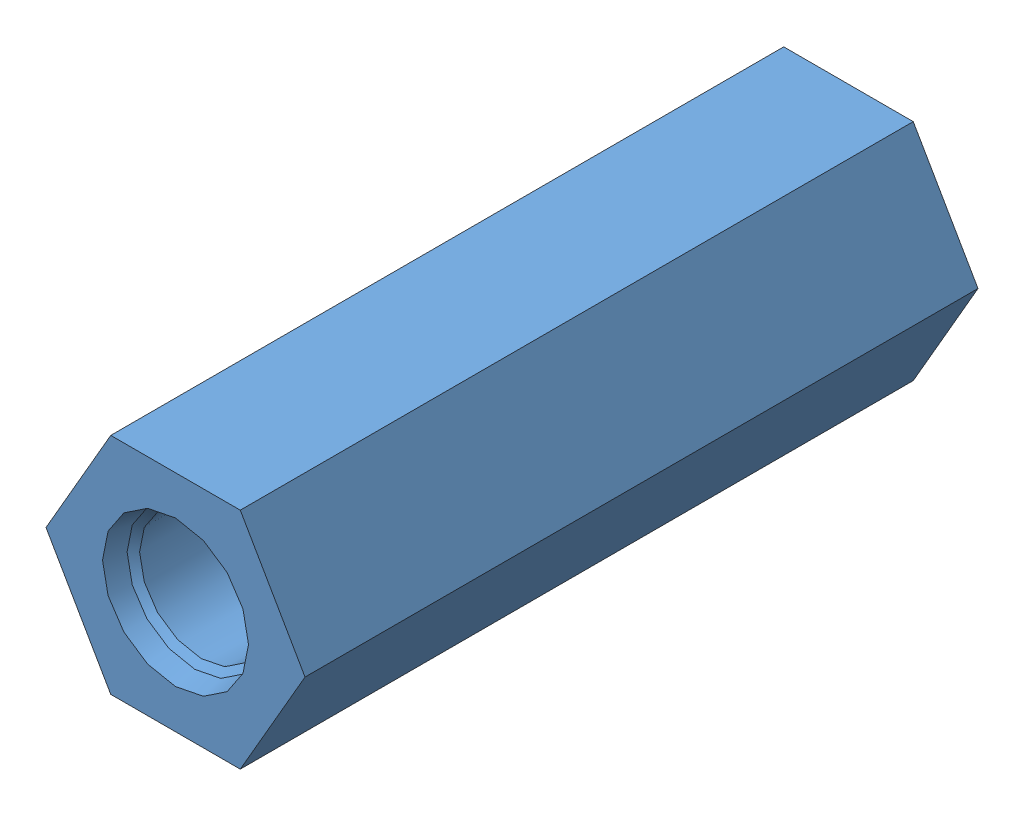
SolidWorks assembly METHALOX IGNITOR ASSEMBLY, configuration Default. Lengths in mm.
Overall size (36.66 31.75 97.26).
2 component instances, 2 part files, 0 mates.
Components (placement in the parent):
- Igniter Hex Rev A-1: Igniter Hex Rev A [Default] at (2.7462 21.8799 -16.314) size (36.66 31.75 97.26)
- AN-8 Union_CB-1: AN-8 Union_CB [50715K263] at (2.7462 21.8799 -20.124) x (0 0 -1) z (-0.866025 0.5 0) (suppressed, hidden)
